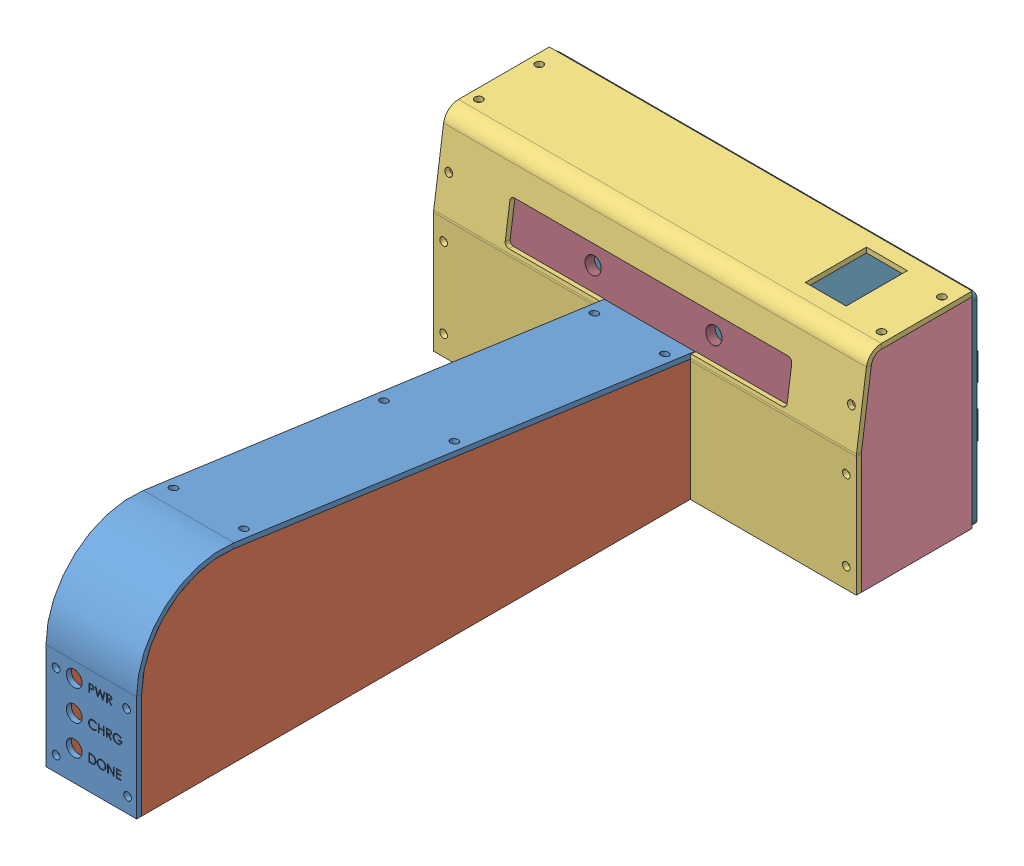
SolidWorks assembly CHARGING, TOP ASSY, configuration Default. Lengths in mm.
Overall size (133.35 64.84 227.6).
63 component instances, 22 part files, 85 mates.
Components (placement in the parent):
- Socket Countersunk Head Cap Screw_AI-11: Socket Countersunk Head Cap Screw_AI [SCHCSCREW 0.086-56x0.188x0.188-HX-N] at (63.5 57.15 -211.2772) x (0 0 1) z (-0.139173 0.990268 0) (suppressed, hidden)
- Socket Countersunk Head Cap Screw_AI-12: Socket Countersunk Head Cap Screw_AI [SCHCSCREW 0.086-56x0.188x0.188-HX-N] at (-63.5 6.35 -211.2772) x (0 0 1) z (-0.139173 0.990268 0) (suppressed, hidden)
- Socket Countersunk Head Cap Screw_AI-13: Socket Countersunk Head Cap Screw_AI [SCHCSCREW 0.086-56x0.188x0.188-HX-N] at (-63.5 57.15 -211.2772) x (0 0 1) z (-0.139173 0.990268 0) (suppressed, hidden)
- Socket Countersunk Head Cap Screw_AI-14: Socket Countersunk Head Cap Screw_AI [SCHCSCREW 0.086-56x0.188x0.188-HX-N] at (63.5 6.35 -211.2772) x (0 0 1) z (-0.139173 0.990268 0) (suppressed, hidden)
- Socket Countersunk Head Cap Screw_AI-1: Socket Countersunk Head Cap Screw_AI [SCHCSCREW 0.086-56x0.188x0.188-HX-N] at (-11.1125 40.6816 -168.2154) x (0 -0.990268 0.139173) z (-0.139173 0.137819 0.980631) (suppressed, hidden)
- Socket Countersunk Head Cap Screw_AI-2: Socket Countersunk Head Cap Screw_AI [SCHCSCREW 0.086-56x0.188x0.188-HX-N] at (-11.1125 59.3389 -35.4618) x (0 -0.990268 0.139173) z (-0.139173 0.137819 0.980631) (suppressed, hidden)
- Socket Countersunk Head Cap Screw_AI-3: Socket Countersunk Head Cap Screw_AI [SCHCSCREW 0.086-56x0.188x0.188-HX-N] at (11.1125 50.0102 -101.8386) x (0 -0.990268 0.139173) z (-0.139173 0.137819 0.980631) (suppressed, hidden)
- Socket Countersunk Head Cap Screw_AI-4: Socket Countersunk Head Cap Screw_AI [SCHCSCREW 0.086-56x0.188x0.188-HX-N] at (-11.1125 50.0102 -101.8386) x (0 -0.990268 0.139173) z (-0.139173 0.137819 0.980631) (suppressed, hidden)
- Socket Countersunk Head Cap Screw_AI-5: Socket Countersunk Head Cap Screw_AI [SCHCSCREW 0.086-56x0.188x0.188-HX-N] at (11.1125 40.6816 -168.2154) x (0 -0.990268 0.139173) z (-0.139173 0.137819 0.980631) (suppressed, hidden)
- Socket Countersunk Head Cap Screw_AI-6: Socket Countersunk Head Cap Screw_AI [SCHCSCREW 0.086-56x0.188x0.188-HX-N] at (11.1125 59.3389 -35.4618) x (0 -0.990268 0.139173) z (-0.139173 0.137819 0.980631) (suppressed, hidden)
- Socket Countersunk Head Cap Screw_AI-7: Socket Countersunk Head Cap Screw_AI [SCHCSCREW 0.086-56x0.188x0.188-HX-N] at (11.1125 28.5968 1.7145) x (0 0 -1) z (1 0 0) (suppressed, hidden)
- Socket Countersunk Head Cap Screw_AI-8: Socket Countersunk Head Cap Screw_AI [SCHCSCREW 0.086-56x0.188x0.188-HX-N] at (11.4452 4.7752 1.7145) x (0 0 -1) z (1 0 0) (suppressed, hidden)
- Socket Countersunk Head Cap Screw_AI-9: Socket Countersunk Head Cap Screw_AI [SCHCSCREW 0.086-56x0.188x0.188-HX-N] at (-11.1125 4.7752 1.7145) x (0 0 -1) z (1 0 0) (suppressed, hidden)
- Socket Countersunk Head Cap Screw_AI-10: Socket Countersunk Head Cap Screw_AI [SCHCSCREW 0.086-56x0.188x0.188-HX-N] at (-11.1125 28.5968 1.7145) x (0 0 -1) z (1 0 0) (suppressed, hidden)
- Socket Countersunk Head Cap Screw_AI-15: Socket Countersunk Head Cap Screw_AI [SCHCSCREW 0.086-56x0.188x0.188-HX-N] at (-63.5 64.9673 -203.2) x (0 -1 0) z (-0.139173 0 0.990268) (suppressed, hidden)
- Socket Countersunk Head Cap Screw_AI-16: Socket Countersunk Head Cap Screw_AI [SCHCSCREW 0.086-56x0.188x0.188-HX-N] at (-63.5 64.9673 -184.15) x (0 -1 0) z (-0.139173 0 0.990268) (suppressed, hidden)
- Socket Countersunk Head Cap Screw_AI-17: Socket Countersunk Head Cap Screw_AI [SCHCSCREW 0.086-56x0.188x0.188-HX-N] at (-63.5 31.528 -172.9105) x (0 0 -1) z (-0.139173 -0.990268 0) (suppressed, hidden)
- Socket Countersunk Head Cap Screw_AI-18: Socket Countersunk Head Cap Screw_AI [SCHCSCREW 0.086-56x0.188x0.188-HX-N] at (-63.5 6.35 -172.9105) x (0 0 -1) z (-0.139173 -0.990268 0) (suppressed, hidden)
- Socket Countersunk Head Cap Screw_AI-19: Socket Countersunk Head Cap Screw_AI [SCHCSCREW 0.086-56x0.188x0.188-HX-N] at (63.5 31.528 -172.9105) x (0 0 -1) z (-0.139173 -0.990268 0) (suppressed, hidden)
- Socket Countersunk Head Cap Screw_AI-20: Socket Countersunk Head Cap Screw_AI [SCHCSCREW 0.086-56x0.188x0.188-HX-N] at (63.5 6.35 -172.9105) x (0 0 -1) z (-0.139173 -0.990268 0) (suppressed, hidden)
- Socket Countersunk Head Cap Screw_AI-21: Socket Countersunk Head Cap Screw_AI [SCHCSCREW 0.086-56x0.188x0.188-HX-N] at (63.5 64.9673 -203.2) x (0 -1 0) z (-0.139173 0 0.990268) (suppressed, hidden)
- Socket Countersunk Head Cap Screw_AI-22: Socket Countersunk Head Cap Screw_AI [SCHCSCREW 0.086-56x0.188x0.188-HX-N] at (63.5 64.9673 -184.15) x (0 -1 0) z (-0.139173 0 0.990268) (suppressed, hidden)
- CHARGING, CHASSIS, TOP ASSY-1: CHARGING, CHASSIS, TOP ASSY [Default] at origin size (133.35 64.84 211.14)
  - CHARGING, PLATE, Cover-1: CHARGING, PLATE, Cover [Default] at origin size (28.57 60.36 176.07)
  - CHARGING, PLATE, Side-4: CHARGING, PLATE, Side [Default] at (-11.1125 0 0) size (6.35 58.77 174.27)
  - CHARGING, PLATE, Side-5: CHARGING, PLATE, Side [Default] at (11.1125 0 0) size (6.35 58.77 174.27)
  - CHARGING, PLATE, Charging Bay Cover-1: CHARGING, PLATE, Charging Bay Cover [Default] at origin size (133.35 64.84 36.51)
  - CHARGING, PLATE, Bay Side-1: CHARGING, PLATE, Bay Side [Default] at (63.5 0 0) size (6.35 63.25 34.92)
  - CHARGING, PLATE, Bay Side-2: CHARGING, PLATE, Bay Side [Default] at (-63.5 0 0) size (6.35 63.25 34.92)
  - CHARGING, PLATE, Rear Base-1: CHARGING, PLATE, Rear Base [Default] at (0 0 -192.0875) size (120.65 3.17 209.55)
- CONNECTOR, MOLEX PANEL MOUNT, 003122045-1: CONNECTOR, MOLEX PANEL MOUNT, 003122045 [Default] at (34.925 12.7 -210.4517) x (-1 0 0) z (0 1 0) size (48.37 31.12 15.24)
- CONNECTOR, MOLEX PANEL MOUNT, 003122045-2: CONNECTOR, MOLEX PANEL MOUNT, 003122045 [Default] at (34.925 28.575 -210.4517) x (-1 0 0) z (0 1 0) size (48.37 31.12 15.24)
- PCB, CHARGE BOARD-2: PCB, CHARGE BOARD [Default] at (-35.6575 20.7967 -178.6) x (-1 0 0) z (0 -1 0) size (38.73 19.02 30.48)
  - PCB, CHARGE BOARD-1: PCB, CHARGE BOARD [Default] x (1 0 0) z (0 1 0) size (38.73 30.48 1.6)
  - HDR1x2_-3: HDR1x2_ [Default] at (-16.8961 3.34 -1.2365) x (0 0 -1) z (-1 0 0) (suppressed, hidden)
  - HDR1x4-1: HDR1x4 [Default] at (-16.966 0.8 12.7485) x (0 0 -1) z (1 0 0) (suppressed, hidden)
  - SO_IC8-1: SO_IC8 [Default] at (-1.5846 1.7 -4.8651) x (0 0 1) z (-1 0 0) (suppressed, hidden)
  - SOT-223-1: SOT-223 [Default] at (9.921 1.5 -5.1354) x (0 0 1) z (-1 0 0) (suppressed, hidden)
  - Resistor 1206-4: Resistor 1206 [Default] at (-1.6904 1.3 -0.7338) x (1 0 0) z (0 0 -1) (suppressed, hidden)
  - Resistor 1206-5: Resistor 1206 [Default] at (-10.6337 1.3 -1.2635) x (1 0 0) z (0 0 -1) (suppressed, hidden)
  - Resistor 1206-6: Resistor 1206 [Default] at (-10.5857 1.3 -3.8039) x (1 0 0) z (0 0 -1) (suppressed, hidden)
  - Resistor 1206-7: Resistor 1206 [Default] at (17.5234 1.3 -11.5247) x (0 0 -1) z (-1 0 0) (suppressed, hidden)
  - Resistor 1206-9: Resistor 1206 [Default] at (-2.8991 1.3 -11.4814) x (0 0 -1) z (-1 0 0) (suppressed, hidden)
  - Resistor 1206-10: Resistor 1206 [Default] at (17.5646 1.3 -0.9643) x (0 0 -1) z (-1 0 0) (suppressed, hidden)
  - Resistor 1206-12: Resistor 1206 [Default] at (7.3429 1.3 -11.5481) x (0 0 -1) z (-1 0 0) (suppressed, hidden)
  - User Library-RES_2010L-1: User Library-RES_2010L [Default] at (15.3929 1.1 3.4133) size (5 0.61 2.5)
    - User Library-RES_2010L_RES_2010_Body_1-1: User Library-RES_2010L_RES_2010_Body_1 [Default] at origin size (4.9 0.56 2.5)
    - User Library-RES_2010L_RES_2010_Lead_1-1: User Library-RES_2010L_RES_2010_Lead_1 [Default] at origin size (0.6 0.6 2.5)
    - User Library-RES_2010L_RES_2010_Lead_1-2: User Library-RES_2010L_RES_2010_Lead_1 [Default] x (-1 0 0) z (0 0 -1) size (0.6 0.6 2.5)
  - Mini blade fuse - 1 to 40 a - 32 v-1: Mini blade fuse - 1 to 40 a - 32 v [3 A] at (-7.7757 15.9356 14.4425) x (1 0 0) z (0 1 0) size (10.9 3.81 16.3)
  - Mini Blade Fuse Holder, PCB-1: Mini Blade Fuse Holder, PCB [Default] at (-2.027 0.8 12.6144) size (14.7 8.64 4.8)
  - Resistor 1206-14: Resistor 1206 [Default] at (17.5733 1.3 -6.3368) x (0 0 -1) z (-1 0 0) (suppressed, hidden)
- User Library-canal rocker switch mr2-1: User Library-canal rocker switch mr2 [MR2-115-C5-BB3N] at (44.45 66.8403 -195.235) x (1 0 0) z (0 1 0) (suppressed, hidden)
- CHARGING, Contacts-1: CHARGING, Contacts [Default] at (-19.05 43.9234 -189.8713) x (0 -0.139173 -0.990268) z (0.871119 -0.486293 0.068344) size (9.53 4.78 4.78)
- CHARGING, Contacts-2: CHARGING, Contacts [Default] at (19.05 43.9234 -189.8713) x (0 -0.139173 -0.990268) z (0.888496 -0.454419 0.063864) size (9.53 4.78 4.78)
- CHARGING, Door-1: CHARGING, Door [Default] at (0 45.7032 -177.2069) x (-1 0 0) z (0 -0.139173 -0.990268) size (88.9 15.88 3)
- CHARGING, PLATE, Rear-1: CHARGING, PLATE, Rear [Default] at (0 31.75 -211.1502) size (133.35 63.5 1.6)
- LEDd5B-4: LEDd5B [Default] at (-4.1872 28.5825 -8.2252) x (-0.999999 -0.001356 0) z (0 0 1) (suppressed, hidden)
- LEDd5B-5: LEDd5B [Default] at (-4.1872 19.0575 -8.2252) x (-0.999999 -0.001356 0) z (0 0 1) (suppressed, hidden)
- LEDd5B-6: LEDd5B [Default] at (-4.1872 9.5325 -8.2252) x (-0.999999 -0.001356 0) z (0 0 1) (suppressed, hidden)
- LABELS-1: LABELS [Default] at (34.6817 46.7156 -211.1502) x (-1 0 0) z (0 0 -1) size (44.45 12.7 0.18)
- Socket Countersunk Head Cap Screw_AI-23: Socket Countersunk Head Cap Screw_AI [SCHCSCREW 0.086-56x0.188x0.188-HX-N] at (-63.5 49.6584 -174.5181) x (0 -0.139173 -0.990268) z (-0.139173 -0.980631 0.137819) (suppressed, hidden)
- Socket Countersunk Head Cap Screw_AI-24: Socket Countersunk Head Cap Screw_AI [SCHCSCREW 0.086-56x0.188x0.188-HX-N] at (63.5 49.6584 -174.5181) x (0 -0.139173 -0.990268) z (-0.139173 -0.980631 0.137819) (suppressed, hidden)
Mates (geometry in assembly coordinates):
- Coincident1: coincident aligned: plane of CONNECTOR, MOLEX PANEL MOUNT, 003122045-1 through (52.07 5.207 -194.8942) normal (0 0 1); plane of CONNECTOR, MOLEX PANEL MOUNT, 003122045-2 through (52.07 21.082 -194.8942) normal (0 0 1)
- Distance1: distance = 3.175 mm anti-aligned: plane of CHARGING, CHASSIS, TOP ASSY-1/CHARGING, PLATE, Charging Bay Cover-1 through (66.675 38.1 -174.625) normal (0 0 -1); plane of PCB, CHARGE BOARD-2/PCB, CHARGE BOARD-1 through (-55.025 36.0367 -177.8) normal (0 0 1)
- Parallel1: parallel aligned: plane of CHARGING, CHASSIS, TOP ASSY-1/CHARGING, PLATE, Charging Bay Cover-1 through (66.675 0 -174.625) normal (0 -1 0); plane of PCB, CHARGE BOARD-2/PCB, CHARGE BOARD-1 through (-16.29 5.5567 -179.4) normal (0 -1 0)
- Coincident6: coincident anti-aligned: plane of CHARGING, CHASSIS, TOP ASSY-1/CHARGING, PLATE, Charging Bay Cover-1 through (66.675 64.8403 -209.55) normal (0 1 0); plane of User Library-canal rocker switch mr2-1 through (36.95 64.8403 -205.735) normal (0 -1 0)
- Distance2: distance = 14.6558 mm anti-aligned: plane of CONNECTOR, MOLEX PANEL MOUNT, 003122045-1 through (52.07 5.207 -194.8942) normal (0 0 1); plane of CHARGING, CHASSIS, TOP ASSY-1/CHARGING, PLATE, Bay Side-1 through (66.675 0 -209.55) normal (0 0 -1)
- Coincident7: coincident aligned: plane of CHARGING, Contacts-1 through (-19.05 43.9234 -189.8713) normal (0 -0.139173 -0.990268); plane of CHARGING, Contacts-2 through (19.05 43.9234 -189.8713) normal (0 -0.139173 -0.990268)
- Concentric1: concentric anti-aligned: cylinder of CHARGING, Contacts-2 through (19.05 43.9234 -189.8713) axis (0 -0.139173 -0.990268) radius 2.3876; cylinder of CHARGING, Door-1 through (19.05 45.4947 -178.6909) axis (0 0.139173 0.990268) radius 2.54
- Concentric2: concentric anti-aligned: cylinder of CHARGING, Contacts-1 through (-19.05 43.9234 -189.8713) axis (0 -0.139173 -0.990268) radius 2.3876; cylinder of CHARGING, Door-1 through (-19.05 45.4947 -178.6909) axis (0 0.139173 0.990268) radius 2.54
- Parallel2: parallel anti-aligned: plane of CHARGING, CHASSIS, TOP ASSY-1/CHARGING, PLATE, Charging Bay Cover-1 through (66.675 63.2528 -178.16) normal (0 -0.139173 -0.990268); plane of CHARGING, Door-1 through (-44.45 53.772 -176.8276) normal (0 0.139173 0.990268)
- Width1: width aligned: plane of CHARGING, CHASSIS, TOP ASSY-1/CHARGING, PLATE, Charging Bay Cover-1 through (-14.2875 39.6723 -173.2429) normal (0 0.990268 -0.139173); plane of CHARGING, CHASSIS, TOP ASSY-1/CHARGING, PLATE, Charging Bay Cover-1 through (-44.45 52.3723 -176.6308) normal (0 -0.990268 0.139173); plane of CHARGING, Door-1 through (44.45 53.3549 -179.7956) normal (0 0.990268 -0.139173); plane of CHARGING, Door-1 through (44.45 37.6344 -177.5862) normal (0 -0.990268 0.139173)
- Coincident8: coincident anti-aligned: plane of CHARGING, Door-1; plane of ? through (0 0 0) normal (1 0 0)
- Distance3: distance = 0 mm anti-aligned: plane of CHARGING, Door-1 through (-44.45 53.772 -176.8276) normal (0 0.139173 0.990268); plane of CHARGING, CHASSIS, TOP ASSY-1/CHARGING, PLATE, Charging Bay Cover-1 through (66.675 63.2528 -178.16) normal (0 -0.139173 -0.990268)
- Coincident9: coincident aligned: plane of ? through (0 0 0) normal (0 0 1); plane of assembly through (0 0 0) normal (0 0 1)
- Coincident10: coincident aligned: plane of ? through (0 0 0) normal (1 0 0); plane of assembly through (0 0 0) normal (1 0 0)
- Coincident11: coincident aligned: plane of ? through (0 0 0) normal (0 1 0); plane of assembly through (0 0 0) normal (0 1 0)
- Coincident15: coincident aligned: plane of CHARGING, PLATE, Rear-1 through (0 31.75 -211.1502) normal (1 0 0); plane of assembly through (0 0 0) normal (1 0 0)
- Coincident16: coincident anti-aligned: plane of CHARGING, CHASSIS, TOP ASSY-1/CHARGING, PLATE, Bay Side-2 through (-60.325 0 -209.55) normal (0 0 -1); plane of CHARGING, PLATE, Rear-1 through (66.675 63.5 -209.55) normal (0 0 1)
- Coincident17: coincident aligned: plane of CHARGING, CHASSIS, TOP ASSY-1/CHARGING, PLATE, Bay Side-2 through (-60.325 0 -174.625) normal (0 -1 0); plane of CHARGING, PLATE, Rear-1 through (-66.675 0 -209.55) normal (0 -1 0)
- Parallel3: parallel aligned: plane of CONNECTOR, MOLEX PANEL MOUNT, 003122045-2 through (52.07 24.003 -226.0092) normal (0 -1 0); plane of CHARGING, PLATE, Rear-1 through (-66.675 0 -209.55) normal (0 -1 0)
- Parallel4: parallel aligned: plane of CONNECTOR, MOLEX PANEL MOUNT, 003122045-1 through (52.07 8.128 -226.0092) normal (0 -1 0); plane of CHARGING, PLATE, Rear-1 through (-66.675 0 -209.55) normal (0 -1 0)
- Distance4: distance = 15.875 mm aligned: plane of CONNECTOR, MOLEX PANEL MOUNT, 003122045-1 through (52.07 8.128 -226.0092) normal (0 -1 0); plane of CONNECTOR, MOLEX PANEL MOUNT, 003122045-2 through (52.07 24.003 -226.0092) normal (0 -1 0)
- Coincident20: coincident aligned: plane of Socket Countersunk Head Cap Screw_AI-7 through (11.1125 28.5968 1.7145) normal (0 0 1); plane of Socket Countersunk Head Cap Screw_AI-8 through (11.4452 4.7752 1.7145) normal (0 0 1)
- Coincident21: coincident aligned: plane of Socket Countersunk Head Cap Screw_AI-9 through (-11.1125 4.7752 1.7145) normal (0 0 1); plane of Socket Countersunk Head Cap Screw_AI-10 through (-11.1125 28.5968 1.7145) normal (0 0 1)
- Coincident22: coincident aligned: plane of Socket Countersunk Head Cap Screw_AI-8 through (11.4452 4.7752 1.7145) normal (0 0 1); plane of Socket Countersunk Head Cap Screw_AI-10 through (-11.1125 28.5968 1.7145) normal (0 0 1)
- Coincident23: coincident aligned: plane of Socket Countersunk Head Cap Screw_AI-1 through (-11.1125 40.6816 -168.2154) normal (0 0.990268 -0.139173); plane of Socket Countersunk Head Cap Screw_AI-2 through (-11.1125 59.3389 -35.4618) normal (0 0.990268 -0.139173)
- Coincident25: coincident aligned: plane of Socket Countersunk Head Cap Screw_AI-1 through (-11.1125 40.6816 -168.2154) normal (0 0.990268 -0.139173); plane of Socket Countersunk Head Cap Screw_AI-3 through (11.1125 50.0102 -101.8386) normal (0 0.990268 -0.139173)
- Coincident26: coincident aligned: plane of Socket Countersunk Head Cap Screw_AI-5 through (11.1125 40.6816 -168.2154) normal (0 0.990268 -0.139173); plane of Socket Countersunk Head Cap Screw_AI-6 through (11.1125 59.3389 -35.4618) normal (0 0.990268 -0.139173)
- Coincident27: coincident aligned: plane of Socket Countersunk Head Cap Screw_AI-4 through (-11.1125 50.0102 -101.8386) normal (0 0.990268 -0.139173); plane of Socket Countersunk Head Cap Screw_AI-5 through (11.1125 40.6816 -168.2154) normal (0 0.990268 -0.139173)
- Coincident28: coincident aligned: plane of Socket Countersunk Head Cap Screw_AI-2 through (-11.1125 59.3389 -35.4618) normal (0 0.990268 -0.139173); plane of Socket Countersunk Head Cap Screw_AI-4 through (-11.1125 50.0102 -101.8386) normal (0 0.990268 -0.139173)
- Concentric3: concentric aligned: cylinder of CHARGING, CHASSIS, TOP ASSY-1/CHARGING, PLATE, Cover-1 through (-11.1125 59.2131 -35.4441) axis (0 0.990268 -0.139173) radius 1.2192; cylinder of Socket Countersunk Head Cap Screw_AI-2 through (-11.1125 59.3389 -35.4618) axis (0 0.990268 -0.139173) radius 1.0922
- Concentric4: concentric aligned: cylinder of CHARGING, CHASSIS, TOP ASSY-1/CHARGING, PLATE, Cover-1 through (-11.1125 40.5558 -168.1977) axis (0 0.990268 -0.139173) radius 1.2192; cylinder of Socket Countersunk Head Cap Screw_AI-1 through (-11.1125 40.6816 -168.2154) axis (0 0.990268 -0.139173) radius 1.0922
- Concentric5: concentric aligned: cylinder of CHARGING, CHASSIS, TOP ASSY-1/CHARGING, PLATE, Cover-1 through (-11.1125 49.8845 -101.8209) axis (0 0.990268 -0.139173) radius 1.2192; cylinder of Socket Countersunk Head Cap Screw_AI-4 through (-11.1125 50.0102 -101.8386) axis (0 0.990268 -0.139173) radius 1.0922
- Concentric6: concentric aligned: cylinder of CHARGING, CHASSIS, TOP ASSY-1/CHARGING, PLATE, Cover-1 through (11.1125 40.5558 -168.1977) axis (0 0.990268 -0.139173) radius 1.2192; cylinder of Socket Countersunk Head Cap Screw_AI-5 through (11.1125 40.6816 -168.2154) axis (0 0.990268 -0.139173) radius 1.0922
- Concentric7: concentric aligned: cylinder of CHARGING, CHASSIS, TOP ASSY-1/CHARGING, PLATE, Cover-1 through (11.1125 49.8845 -101.8209) axis (0 0.990268 -0.139173) radius 1.2192; cylinder of Socket Countersunk Head Cap Screw_AI-3 through (11.1125 50.0102 -101.8386) axis (0 0.990268 -0.139173) radius 1.0922
- Concentric8: concentric aligned: cylinder of CHARGING, CHASSIS, TOP ASSY-1/CHARGING, PLATE, Cover-1 through (11.1125 59.2131 -35.4441) axis (0 0.990268 -0.139173) radius 1.2192; cylinder of Socket Countersunk Head Cap Screw_AI-6 through (11.1125 59.3389 -35.4618) axis (0 0.990268 -0.139173) radius 1.0922
- Distance5: distance = 0.127 mm aligned: plane of CHARGING, CHASSIS, TOP ASSY-1/CHARGING, PLATE, Cover-1 through (14.2875 39.6721 -174.4859) normal (0 0.990268 -0.139173); plane of Socket Countersunk Head Cap Screw_AI-2 through (-11.1125 59.3389 -35.4618) normal (0 0.990268 -0.139173)
- Concentric9: concentric aligned: cylinder of CHARGING, CHASSIS, TOP ASSY-1/CHARGING, PLATE, Cover-1 through (11.1125 28.5968 1.5875) axis (0 0 1) radius 1.2192; cylinder of Socket Countersunk Head Cap Screw_AI-7 through (11.1125 28.5968 1.7145) axis (0 0 1) radius 1.0922
- Concentric10: concentric aligned: cylinder of CHARGING, CHASSIS, TOP ASSY-1/CHARGING, PLATE, Cover-1 through (11.4452 4.7752 1.5875) axis (0 0 1) radius 1.2192; cylinder of Socket Countersunk Head Cap Screw_AI-8 through (11.4452 4.7752 1.7145) axis (0 0 1) radius 1.0922
- Concentric11: concentric aligned: cylinder of CHARGING, CHASSIS, TOP ASSY-1/CHARGING, PLATE, Cover-1 through (-11.1125 4.7752 1.5875) axis (0 0 1) radius 1.2192; cylinder of Socket Countersunk Head Cap Screw_AI-9 through (-11.1125 4.7752 1.7145) axis (0 0 1) radius 1.0922
- Concentric12: concentric aligned: cylinder of CHARGING, CHASSIS, TOP ASSY-1/CHARGING, PLATE, Cover-1 through (-11.1125 28.5968 1.5875) axis (0 0 1) radius 1.2192; cylinder of Socket Countersunk Head Cap Screw_AI-10 through (-11.1125 28.5968 1.7145) axis (0 0 1) radius 1.0922
- Distance6: distance = 0.127 mm aligned: plane of CHARGING, CHASSIS, TOP ASSY-1/CHARGING, PLATE, Cover-1 through (14.2875 33.372 1.5875) normal (0 0 1); plane of Socket Countersunk Head Cap Screw_AI-10 through (-11.1125 28.5968 1.7145) normal (0 0 1)
- Coincident32: coincident aligned: plane of ? through (-7.8896 30.3876 -4.5125) normal (0 0 -1); plane of ? through (-7.8896 20.8626 -4.5125) normal (0 0 -1)
- Coincident33: coincident aligned: plane of ? through (-7.8896 20.8626 -4.5125) normal (0 0 -1); plane of ? through (-7.8896 11.3376 -4.5125) normal (0 0 -1)
- Coincident34: coincident aligned: plane of ? through (-7.8853 17.2525 -4.5125) normal (-1 0 0); plane of ? through (-7.8853 7.7275 -4.5125) normal (-1 0 0)
- Coincident35: coincident aligned: plane of ? through (-7.8853 26.7775 -4.5125) normal (-1 0 0); plane of ? through (-7.8853 17.2525 -4.5125) normal (-1 0 0)
- Coincident36: coincident anti-aligned: plane of CHARGING, CHASSIS, TOP ASSY-1/CHARGING, PLATE, Cover-1 through (14.2875 33.372 1.5875) normal (0 0 1); circle of ?
- Concentric13: concentric anti-aligned: cylinder of CHARGING, CHASSIS, TOP ASSY-1/CHARGING, PLATE, Cover-1 through (-5.3975 28.575 0) axis (0 0 1) radius 2.5; cylinder of ? through (-5.3975 28.575 -3.5125) axis (0 0 -1) radius 2.5
- Concentric14: concentric anti-aligned: cylinder of CHARGING, CHASSIS, TOP ASSY-1/CHARGING, PLATE, Cover-1 through (-5.3975 19.05 0) axis (0 0 1) radius 2.5; cylinder of ? through (-5.3975 19.05 -3.5125) axis (0 0 -1) radius 2.5
- Concentric15: concentric anti-aligned: cylinder of CHARGING, CHASSIS, TOP ASSY-1/CHARGING, PLATE, Cover-1 through (-5.3975 9.525 0) axis (0 0 1) radius 2.5; cylinder of ? through (-5.3975 9.525 -3.5125) axis (0 0 -1) radius 2.5
- Coincident37: coincident aligned: plane of Socket Countersunk Head Cap Screw_AI-11 through (63.5 57.15 -211.2772) normal (0 0 -1); plane of Socket Countersunk Head Cap Screw_AI-14 through (63.5 6.35 -211.2772) normal (0 0 -1)
- Coincident38: coincident aligned: plane of Socket Countersunk Head Cap Screw_AI-12 through (-63.5 6.35 -211.2772) normal (0 0 -1); plane of Socket Countersunk Head Cap Screw_AI-13 through (-63.5 57.15 -211.2772) normal (0 0 -1)
- Coincident39: coincident aligned: plane of Socket Countersunk Head Cap Screw_AI-11 through (63.5 57.15 -211.2772) normal (0 0 -1); plane of Socket Countersunk Head Cap Screw_AI-12 through (-63.5 6.35 -211.2772) normal (0 0 -1)
- Concentric16: concentric aligned: cylinder of CHARGING, PLATE, Rear-1 through (63.5 6.35 -211.1502) axis (0 0 -1) radius 1.2192; cylinder of Socket Countersunk Head Cap Screw_AI-14 through (63.5 6.35 -211.2772) axis (0 0 -1) radius 1.0922
- Concentric17: concentric aligned: cylinder of CHARGING, PLATE, Rear-1 through (63.5 57.15 -211.1502) axis (0 0 -1) radius 1.2192; cylinder of Socket Countersunk Head Cap Screw_AI-11 through (63.5 57.15 -211.2772) axis (0 0 -1) radius 1.0922
- Concentric18: concentric aligned: cylinder of CHARGING, PLATE, Rear-1 through (-63.5 57.15 -211.1502) axis (0 0 -1) radius 1.2192; cylinder of Socket Countersunk Head Cap Screw_AI-13 through (-63.5 57.15 -211.2772) axis (0 0 -1) radius 1.0922
- Concentric19: concentric aligned: cylinder of CHARGING, PLATE, Rear-1 through (-63.5 6.35 -211.1502) axis (0 0 -1) radius 1.2192; cylinder of Socket Countersunk Head Cap Screw_AI-12 through (-63.5 6.35 -211.2772) axis (0 0 -1) radius 1.0922
- Distance7: distance = 0.127 mm aligned: plane of CHARGING, PLATE, Rear-1 through (66.675 63.5 -211.1502) normal (0 0 -1); plane of Socket Countersunk Head Cap Screw_AI-12 through (-63.5 6.35 -211.2772) normal (0 0 -1)
- Distance8: distance = 6.35 mm aligned: plane of CHARGING, Contacts-1 through (-19.05 45.249 -180.439) normal (0 0.139173 0.990268); plane of CHARGING, CHASSIS, TOP ASSY-1/CHARGING, PLATE, Charging Bay Cover-1 through (66.675 63.4737 -176.5879) normal (0 0.139173 0.990268)
- Coincident40: coincident aligned: plane of Socket Countersunk Head Cap Screw_AI-19 through (63.5 31.528 -172.9105) normal (0 0 1); plane of Socket Countersunk Head Cap Screw_AI-20 through (63.5 6.35 -172.9105) normal (0 0 1)
- Coincident41: coincident aligned: plane of Socket Countersunk Head Cap Screw_AI-21 through (63.5 64.9673 -203.2) normal (0 1 0); plane of Socket Countersunk Head Cap Screw_AI-22 through (63.5 64.9673 -184.15) normal (0 1 0)
- Concentric20: concentric aligned: cylinder of CHARGING, CHASSIS, TOP ASSY-1/CHARGING, PLATE, Charging Bay Cover-1 through (63.5 64.8403 -203.2) axis (0 1 0) radius 1.2192; cylinder of Socket Countersunk Head Cap Screw_AI-21 through (63.5 64.9673 -203.2) axis (0 1 0) radius 1.0922
- Concentric21: concentric aligned: cylinder of CHARGING, CHASSIS, TOP ASSY-1/CHARGING, PLATE, Charging Bay Cover-1 through (63.5 64.8403 -184.15) axis (0 1 0) radius 1.2192; cylinder of Socket Countersunk Head Cap Screw_AI-22 through (63.5 64.9673 -184.15) axis (0 1 0) radius 1.0922
- Coincident42: coincident aligned: plane of Socket Countersunk Head Cap Screw_AI-15 through (-63.5 64.9673 -203.2) normal (0 1 0); plane of Socket Countersunk Head Cap Screw_AI-22 through (63.5 64.9673 -184.15) normal (0 1 0)
- Coincident43: coincident aligned: plane of Socket Countersunk Head Cap Screw_AI-15 through (-63.5 64.9673 -203.2) normal (0 1 0); plane of Socket Countersunk Head Cap Screw_AI-16 through (-63.5 64.9673 -184.15) normal (0 1 0)
- Concentric22: concentric aligned: cylinder of CHARGING, CHASSIS, TOP ASSY-1/CHARGING, PLATE, Charging Bay Cover-1 through (-63.5 64.8403 -203.2) axis (0 1 0) radius 1.2192; cylinder of Socket Countersunk Head Cap Screw_AI-15 through (-63.5 64.9673 -203.2) axis (0 1 0) radius 1.0922
- Concentric23: concentric aligned: cylinder of CHARGING, CHASSIS, TOP ASSY-1/CHARGING, PLATE, Charging Bay Cover-1 through (-63.5 64.8403 -184.15) axis (0 1 0) radius 1.2192; cylinder of Socket Countersunk Head Cap Screw_AI-16 through (-63.5 64.9673 -184.15) axis (0 1 0) radius 1.0922
- Distance9: distance = 0.127 mm aligned: plane of Socket Countersunk Head Cap Screw_AI-15 through (-63.5 64.9673 -203.2) normal (0 1 0); plane of CHARGING, CHASSIS, TOP ASSY-1/CHARGING, PLATE, Charging Bay Cover-1 through (66.675 64.8403 -209.55) normal (0 1 0)
- Concentric24: concentric aligned: cylinder of CHARGING, CHASSIS, TOP ASSY-1/CHARGING, PLATE, Charging Bay Cover-1 through (-63.5 31.528 -173.0375) axis (0 0 1) radius 1.2192; cylinder of Socket Countersunk Head Cap Screw_AI-17 through (-63.5 31.528 -172.9105) axis (0 0 1) radius 1.0922
- Coincident44: coincident aligned: plane of Socket Countersunk Head Cap Screw_AI-17 through (-63.5 31.528 -172.9105) normal (0 0 1); plane of Socket Countersunk Head Cap Screw_AI-18 through (-63.5 6.35 -172.9105) normal (0 0 1)
- Concentric25: concentric aligned: cylinder of CHARGING, CHASSIS, TOP ASSY-1/CHARGING, PLATE, Charging Bay Cover-1 through (-63.5 6.35 -173.0375) axis (0 0 1) radius 1.2192; cylinder of Socket Countersunk Head Cap Screw_AI-18 through (-63.5 6.35 -172.9105) axis (0 0 1) radius 1.0922
- Coincident45: coincident aligned: plane of Socket Countersunk Head Cap Screw_AI-17 through (-63.5 31.528 -172.9105) normal (0 0 1); plane of Socket Countersunk Head Cap Screw_AI-19 through (63.5 31.528 -172.9105) normal (0 0 1)
- Concentric26: concentric aligned: cylinder of CHARGING, CHASSIS, TOP ASSY-1/CHARGING, PLATE, Charging Bay Cover-1 through (63.5 31.528 -173.0375) axis (0 0 1) radius 1.2192; cylinder of Socket Countersunk Head Cap Screw_AI-19 through (63.5 31.528 -172.9105) axis (0 0 1) radius 1.0922
- Concentric27: concentric aligned: cylinder of CHARGING, CHASSIS, TOP ASSY-1/CHARGING, PLATE, Charging Bay Cover-1 through (63.5 6.35 -173.0375) axis (0 0 1) radius 1.2192; cylinder of Socket Countersunk Head Cap Screw_AI-20 through (63.5 6.35 -172.9105) axis (0 0 1) radius 1.0922
- Distance10: distance = 0.127 mm aligned: plane of CHARGING, CHASSIS, TOP ASSY-1/CHARGING, PLATE, Charging Bay Cover-1 through (66.675 38.1 -173.0375) normal (0 0 1); plane of Socket Countersunk Head Cap Screw_AI-20 through (63.5 6.35 -172.9105) normal (0 0 1)
- Coincident46: coincident anti-aligned: plane of CHARGING, PLATE, Rear-1 through (66.675 63.5 -211.1502) normal (0 0 -1); plane of LABELS-1 through (14.3617 51.1606 -211.1502) normal (0 0 1)
- Parallel5: parallel: plane of CHARGING, PLATE, Rear-1 through (-66.675 63.5 -209.55) normal (0 1 0); line of LABELS-1 through (14.3617 53.0656 -211.328) axis (1 0 0)
- Width2: width: plane of CHARGING, CHASSIS, TOP ASSY-1/CHARGING, PLATE, Charging Bay Cover-1 through (37.9984 63.2528 -185.583) normal (1 0 0); plane of CHARGING, CHASSIS, TOP ASSY-1/CHARGING, PLATE, Charging Bay Cover-1 through (50.9016 63.2528 -185.583) normal (-1 0 0); plane of User Library-canal rocker switch mr2-1 through (38 53.1403 -186.485) normal (-1 0 0); plane of User Library-canal rocker switch mr2-1 through (50.9 53.1403 -203.985) normal (1 0 0)
- Width3: width: plane of CHARGING, CHASSIS, TOP ASSY-1/CHARGING, PLATE, Charging Bay Cover-1 through (37.9984 63.2528 -185.583) normal (0 0 -1); plane of CHARGING, CHASSIS, TOP ASSY-1/CHARGING, PLATE, Charging Bay Cover-1 through (37.9984 63.2528 -204.887) normal (0 0 1); plane of User Library-canal rocker switch mr2-1 through (38 53.1403 -186.485) normal (0 0 1); plane of User Library-canal rocker switch mr2-1 through (50.9 53.1403 -203.985) normal (0 0 -1)
- Width4: width: plane of CHARGING, PLATE, Rear-1 through (15.7353 22.987 -209.55) normal (1 0 0); plane of CHARGING, PLATE, Rear-1 through (54.1147 22.987 -209.55) normal (-1 0 0); plane of CONNECTOR, MOLEX PANEL MOUNT, 003122045-2 through (17.78 28.575 -210.4517) normal (-1 0 0); plane of CONNECTOR, MOLEX PANEL MOUNT, 003122045-2 through (52.07 28.575 -210.4517) normal (1 0 0)
- Width5: width: plane of CONNECTOR, MOLEX PANEL MOUNT, 003122045-2 through (52.07 33.147 -197.9422) normal (0 1 0); plane of CONNECTOR, MOLEX PANEL MOUNT, 003122045-2 through (52.07 24.003 -226.0092) normal (0 -1 0); plane of CHARGING, PLATE, Rear-1 through (54.1147 22.987 -209.55) normal (0 1 0); plane of CHARGING, PLATE, Rear-1 through (54.1147 34.163 -209.55) normal (0 -1 0)
- Coincident47: coincident aligned: plane of CONNECTOR, MOLEX PANEL MOUNT, 003122045-1 through (17.78 12.7 -210.4517) normal (-1 0 0); plane of CONNECTOR, MOLEX PANEL MOUNT, 003122045-2 through (17.78 28.575 -210.4517) normal (-1 0 0)
- Coincident48: coincident aligned: plane of Socket Countersunk Head Cap Screw_AI-23 through (-63.5 49.6584 -174.5181) normal (0 0.139173 0.990268); plane of Socket Countersunk Head Cap Screw_AI-24 through (63.5 49.6584 -174.5181) normal (0 0.139173 0.990268)
- Concentric28: concentric aligned: cylinder of CHARGING, CHASSIS, TOP ASSY-1/CHARGING, PLATE, Charging Bay Cover-1 through (63.5 49.6407 -174.6438) axis (0 0.139173 0.990268) radius 1.2192; cylinder of Socket Countersunk Head Cap Screw_AI-24 through (63.5 49.6584 -174.5181) axis (0 0.139173 0.990268) radius 1.0922
- Concentric29: concentric aligned: cylinder of CHARGING, CHASSIS, TOP ASSY-1/CHARGING, PLATE, Charging Bay Cover-1 through (-63.5 49.6407 -174.6438) axis (0 0.139173 0.990268) radius 1.2192; cylinder of Socket Countersunk Head Cap Screw_AI-23 through (-63.5 49.6584 -174.5181) axis (0 0.139173 0.990268) radius 1.0922
- Distance11: distance = 0.127 mm aligned: plane of Socket Countersunk Head Cap Screw_AI-23 through (-63.5 49.6584 -174.5181) normal (0 0.139173 0.990268); plane of CHARGING, CHASSIS, TOP ASSY-1/CHARGING, PLATE, Charging Bay Cover-1 through (66.675 63.4737 -176.5879) normal (0 0.139173 0.990268)
